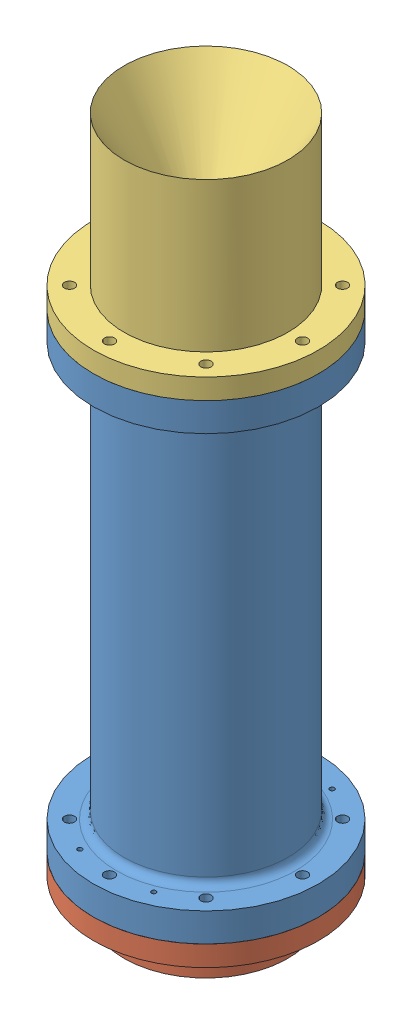
SolidWorks assembly Temperature_Analysis, configuration Default. Lengths in mm.
Overall size (139.7 443.83 139.7).
3 component instances, 3 part files, 4 mates.
Components (placement in the parent):
- Combustion Chamber TST1 (1)-1: Combustion Chamber TST1 (1) [Default] at (-45.0491 -118.8839 5.3156) size (139.7 292.1 139.7)
- Injector EXP9A with holes for slide hammer mount-1: Injector EXP9A with holes for slide hammer mount [Default] at (-45.0491 -118.8839 5.3156) x (1 0 0) z (0 0 -1) size (139.7 46.35 139.7)
- Nozzle-1: Nozzle [Default] at (-45.0491 206.2633 5.3156) x (0 1 0) z (0 0 -1) size (105.37 139.7 139.7)
Mates (geometry in assembly coordinates):
- Concentric3: concentric anti-aligned: cylinder of Combustion Chamber TST1 (1)-1 through (-45.0491 -101.1039 5.3156) axis (0 -1 0) radius 69.85; cylinder of Injector EXP9A with holes for slide hammer mount-1 through (-45.0491 -131.5839 5.3156) axis (0 1 0) radius 69.85
- Coincident2: coincident aligned: circle of Combustion Chamber TST1 (1)-1; circle of Injector EXP9A with holes for slide hammer mount-1
- Coincident3: coincident: circle of Combustion Chamber TST1 (1)-1; circle of Nozzle-1
- Concentric4: concentric anti-aligned: cylinder of Combustion Chamber TST1 (1)-1 through (-45.0491 155.4361 5.3156) axis (0 1 0) radius 69.85; cylinder of Nozzle-1 through (-45.0491 206.2633 5.3156) axis (0 -1 0) radius 69.85
